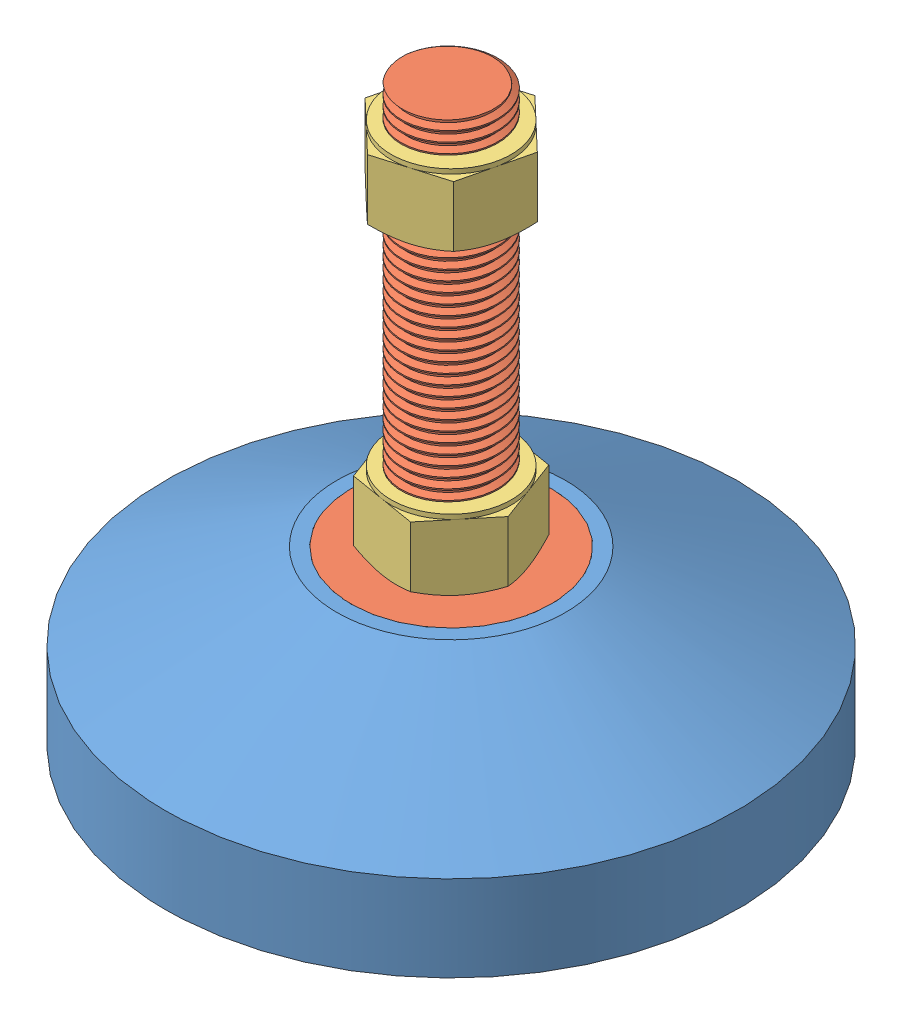
SolidWorks assembly Soporte, configuration Predeterminado. Lengths in mm.
Overall size (100 100.96 100).
4 component instances, 3 part files, 6 mates.
Components (placement in the parent):
- Goma de sopote-1: Goma de sopote [Predeterminado] at (4.1791 -9.6487 100) size (100 30 100)
- Tornillo roscado de sopote-1: Tornillo roscado de sopote [Predeterminado] at (4.1791 -9.6487 100) x (0.414703 0 0.909957) z (-0.909957 0 0.414703) size (55 100.96 55)
- hex nut heavy_am-1: hex nut heavy_am [B18.2.4.6M - Heavy hex nut,  M12 x 1.75 --W-N] at (4.1791 20.3513 100) x (-0.936525 0 0.350601) z (0 -1 0) size (21 24.25 12.3)
- hex nut heavy_am-2: hex nut heavy_am [B18.2.4.6M - Heavy hex nut,  M12 x 1.75 --W-N] at (4.1791 72.6513 100) x (0.689434 0 -0.724348) z (0 -1 0) size (21 24.25 12.3)
Mates (geometry in assembly coordinates):
- Concéntrica1: concentric anti-aligned: cylinder of Goma de sopote-1 through (4.1791 -9.6487 100) axis (0 1 0) radius 17.5; cylinder of Tornillo roscado de sopote-1 through (4.1791 20.3513 100) axis (0 -1 0) radius 17.5
- Coincidente1: coincident anti-aligned: plane of Goma de sopote-1 through (4.1791 0.3513 100) normal (0 -1 0); plane of Tornillo roscado de sopote-1 through (4.1791 0.3513 100) normal (0 1 0)
- Concéntrica2: concentric aligned: cylinder of Tornillo roscado de sopote-1 through (4.1791 90.3513 100) axis (0 -1 0) radius 7.5; cylinder of hex nut heavy_am-1 through (4.1791 45.3888 100) axis (0 -1 0) radius 6
- Concéntrica3: concentric aligned: cylinder of Tornillo roscado de sopote-1 through (4.1791 90.3513 100) axis (0 -1 0) radius 7.5; cylinder of hex nut heavy_am-2 through (4.1791 97.6888 100) axis (0 -1 0) radius 6
- Coincidente2: coincident anti-aligned: plane of Tornillo roscado de sopote-1 through (4.1791 20.3513 100) normal (0 1 0); plane of hex nut heavy_am-1 through (23.8462 20.3513 92.6374) normal (0 -1 0)
- Distancia1: distance = 40 mm anti-aligned: plane of hex nut heavy_am-1 through (23.8462 32.6513 92.6374) normal (0 1 0); plane of hex nut heavy_am-2 through (-10.299 72.6513 115.2113) normal (0 -1 0)
